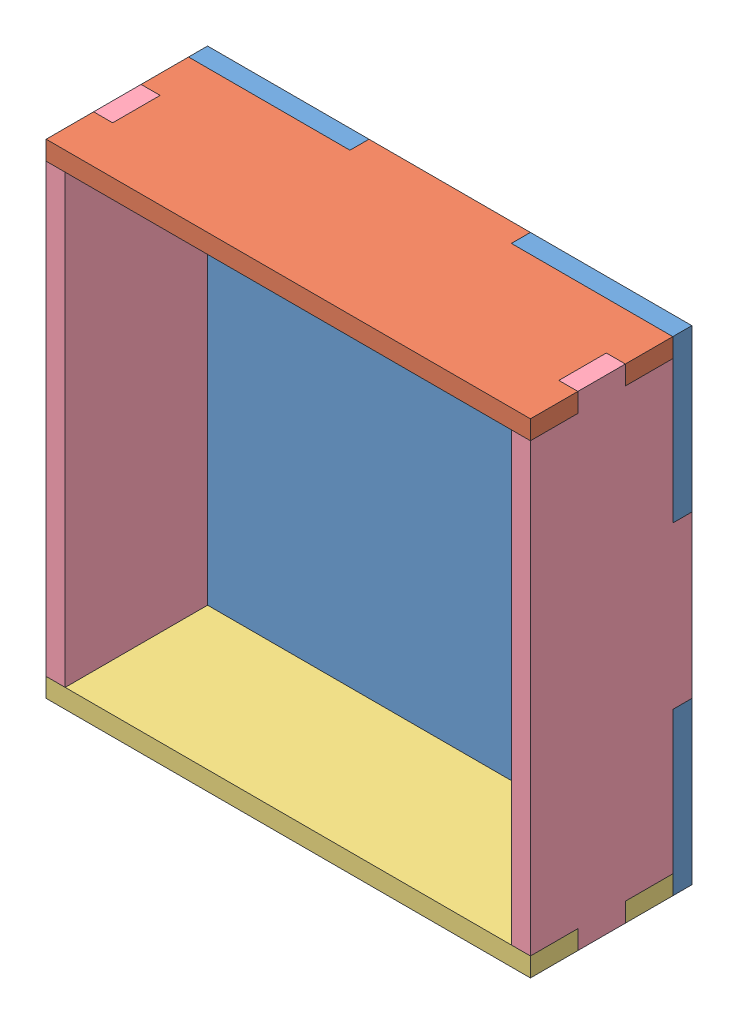
SolidWorks assembly drawer, configuration 3x3x1. Lengths in mm.
Overall size (76.2 76.2 25.4).
5 component instances, 4 part files, 15 mates.
Components (placement in the parent):
- bottom-1: bottom [3x3] at (-17.6955 -22.6147 24.7018) size (76.2 76.2 3)
- front-1: front [3x1] at (44.8337 50.5881 22.7706) x (-1 0 0) z (0 1 0)
- back-1: back [3x1] at (-2.3398 -19.6175 23.7813) x (1 0 0) z (0 -1 0)
- side-3: side [3x1] at (58.5045 49.9982 16.8298) x (0 -1 0) z (-1 0 0) size (76.2 25.4 3)
- side-4: side [3x1] at (-17.6955 -19.0277 16.8298) x (0 1 0) z (1 0 0) size (76.2 25.4 3)
Mates (geometry in assembly coordinates):
- Coincident1: coincident aligned: plane of bottom-1 through (-17.6955 53.5853 27.699) normal (0 1 0); plane of front-1 through (-17.6955 53.5853 50.1018) normal (0 1 0)
- Coincident2: coincident anti-aligned: plane of bottom-1 through (-17.6955 2.7853 27.699) normal (0 0 1); plane of front-1 through (-17.6955 53.5853 27.699) normal (0 0 -1)
- Coincident4: coincident aligned: plane of bottom-1 through (-17.6955 2.7853 24.7018) normal (0 0 -1); plane of back-1 through (7.7045 -22.6147 24.7018) normal (0 0 -1)
- Coincident5: coincident aligned: line of bottom-1 through (7.7045 -19.6175 24.7018) axis (1 0 0); line of back-1 through (7.7045 -19.6175 24.7018) axis (1 0 0)
- Coincident7: coincident aligned: plane of bottom-1 through (-17.6955 -22.6147 27.699) normal (-1 0 0); plane of back-1 through (-17.6955 -22.6147 27.699) normal (-1 0 0)
- Coincident8: coincident anti-aligned: plane of bottom-1 through (55.3295 78.9853 27.8768) normal (1 0 0); plane of side-3 through (55.3295 126.6103 35.2851) normal (-1 0 0)
- Coincident9: coincident aligned: plane of front-1 through (58.5045 129.7853 50.1018) normal (0 0 1); plane of side-3 through (55.3295 126.6103 50.1018) normal (0 0 1)
- Coincident10: coincident aligned: plane of front-1 through (28.0245 129.7853 37.4018) normal (0 1 0); plane of side-3 through (55.3295 129.7853 35.2851) normal (0 1 0)
- Coincident11: coincident aligned: plane of front-1 through (-17.6955 53.5853 50.1018) normal (0 1 0); plane of side-3 through (55.5073 53.5853 35.1666) normal (0 1 0)
- Coincident12: coincident aligned: plane of front-1 through (58.5045 53.5853 42.6342) normal (1 0 0); plane of side-3 through (58.5045 50.5881 35.1666) normal (1 0 0)
- Coincident13: coincident aligned: plane of front-1 through (12.7845 53.5853 50.1018) normal (0 0 1); plane of side-3 through (55.5073 50.5881 50.1018) normal (0 0 1)
- Coincident16: coincident aligned: plane of bottom-1 through (58.5045 28.1853 27.699) normal (1 0 0); plane of side-3 through (58.5045 50.5881 35.1666) normal (1 0 0)
- Coincident17: coincident aligned: plane of front-1 through (-17.6955 53.5853 50.1018) normal (0 1 0); plane of side-4 through (-14.6983 53.5853 35.1666) normal (0 1 0)
- Coincident19: coincident aligned: plane of bottom-1 through (-17.6955 2.7853 24.7018) normal (0 0 -1); plane of side-4 through (-14.6983 2.7853 24.7018) normal (0 0 -1)
- Coincident20: coincident aligned: plane of bottom-1 through (-17.6955 28.1853 27.699) normal (-1 0 0); plane of side-4 through (-17.6955 -19.6175 35.1666) normal (-1 0 0)
